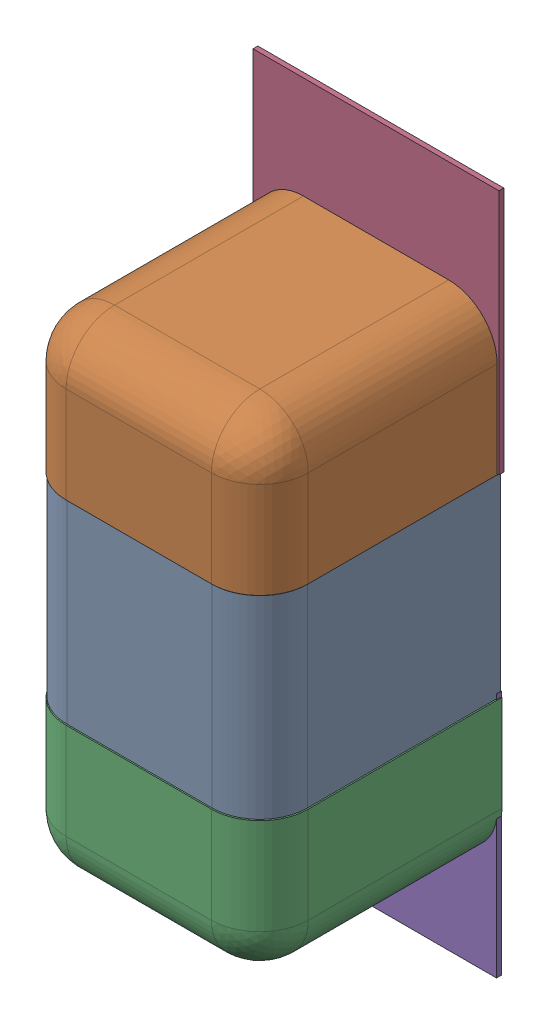
SolidWorks assembly C69, configuration Défaut. Lengths in mm.
Overall size (0.51 1.41 0.5).
8 component instances, 4 part files, 0 mates.
Components (placement in the parent):
- 6501210464-1: 6501210464 [Défaut] at (22.0726 -36.0608 0) x (0 -1 0) z (-1 0 0) size (1 0.5 0.5)
  - Open CASCADE STEP translator 7.5 2.33.1.1-1: Open CASCADE STEP translator 7.5 2.33.1.1 [Défaut] at origin size (0.4 0.5 0.5)
  - Open CASCADE STEP translator 7.5 2.33.1.2-1: Open CASCADE STEP translator 7.5 2.33.1.2 [Défaut] at origin size (0.3 0.5 0.5)
  - Open CASCADE STEP translator 7.5 2.33.1.3-1: Open CASCADE STEP translator 7.5 2.33.1.3 [Défaut] at origin size (0.3 0.5 0.5)
- 6504207776-1: 6504207776 [Défaut] at (22.0726 -35.6035 0) size (0.51 0.51 0.01)
  - Extruded-1: Extruded [Défaut] at origin size (0.51 0.51 0.01)
- 6504207776-2: 6504207776 [Défaut] at (22.0674 -36.5058 0) size (0.51 0.51 0.01)
  - Extruded-1: Extruded [Défaut] at origin size (0.51 0.51 0.01)
